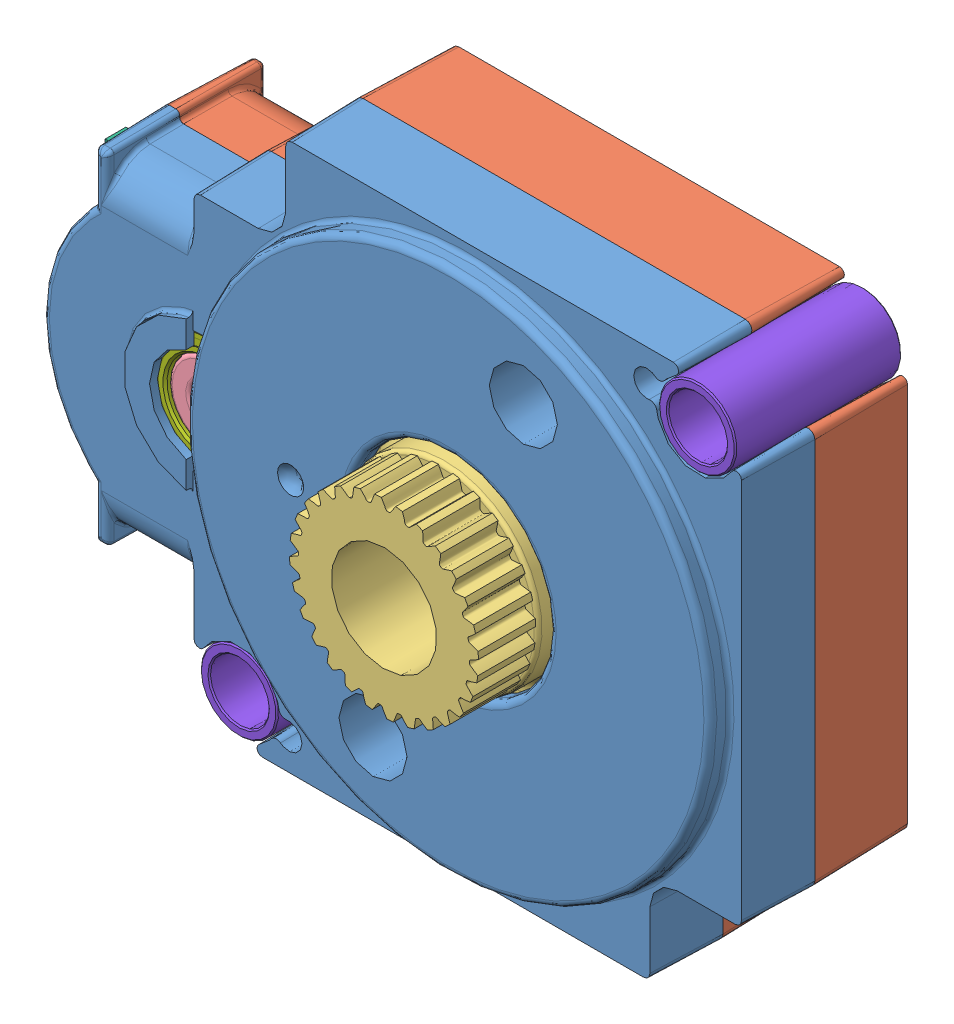
SolidWorks assembly VersaPlanetary_Integrated_Encoder_217-50461, configuration Default. Lengths in mm.
Overall size (58.21 43.13 22.65).
11 component instances, 10 part files, 0 mates.
Components (placement in the parent):
- 217-4783-001 Rev3_1-1: 217-4783-001 Rev3_1 [Default] at (0 0 2.75) size (53.55 42 11.11)
- 217-4783-002 Rev7_Sealed Config_1-1: 217-4783-002 Rev7_Sealed Config_1 [Default] at (0 0 -7.2) x (0 1 0) z (0 0 1) size (42 51.56 9.32)
- 217-4783-005 Rev7_40t_spur_REF_14deg_1-1: 217-4783-005 Rev7_40t_spur_REF_14deg_1 [Default] at (0 0 5.95) x (0.660339 0.750968 0) z (0 0 1) size (21.16 21.1 17.1)
- 217-4783-004 Rev2_40t_spur_REF_14deg_1-1: 217-4783-004 Rev2_40t_spur_REF_14deg_1 [Default] at (-20.05 0 5.2) x (-0.718289 0.695745 0) z (0 0 1) size (21.07 21.07 4.88)
- 217-4783-008 Rev2_1-1: 217-4783-008 Rev2_1 [Default] at (-20.05 0 2.2) x (0.307149 -0.951661 0) z (0.951661 0.307149 0) size (5 4 5)
- PCBA Rev3_1-1: PCBA Rev3_1 [Default] at (-20.05 0 -2.1252) x (0 1 0) z (-1 0 0) size (15.93 10.15 24.58)
- 217-2788-001 Rev3_57155K375_1-1: 217-2788-001 Rev3_57155K375_1 [Default] at (-20.05 0 3.8125) x (-0.99574 0.092202 0) z (0 0 1) size (9.53 9.53 3.17)
- 217-4783-006 Rev3_1-1: 217-4783-006 Rev3_1 [Default] at (17.5 17.5 -0.85) x (-0.867641 0.497191 0) z (0 0 1) size (5.9 5.9 12.7)
- 217-4783-006 Rev3_1-2: 217-4783-006 Rev3_1 [Default] at (-17.5 -17.5 -0.85) x (0.825154 -0.564908 0) z (0 0 1) size (5.9 5.9 12.7)
- 217-4783-007 Rev1_1-1: 217-4783-007 Rev1_1 [Default] at (-16.45 0 -5.2) x (0 1 0) z (0 0 1) size (6 10.71 3.56)
- 217-4783-003 Rev4_1-1: 217-4783-003 Rev4_1 [Default] at (-20.05 0 -1.02) x (0 1 0) z (0 0 1) size (23.4 21.71 4.21)
